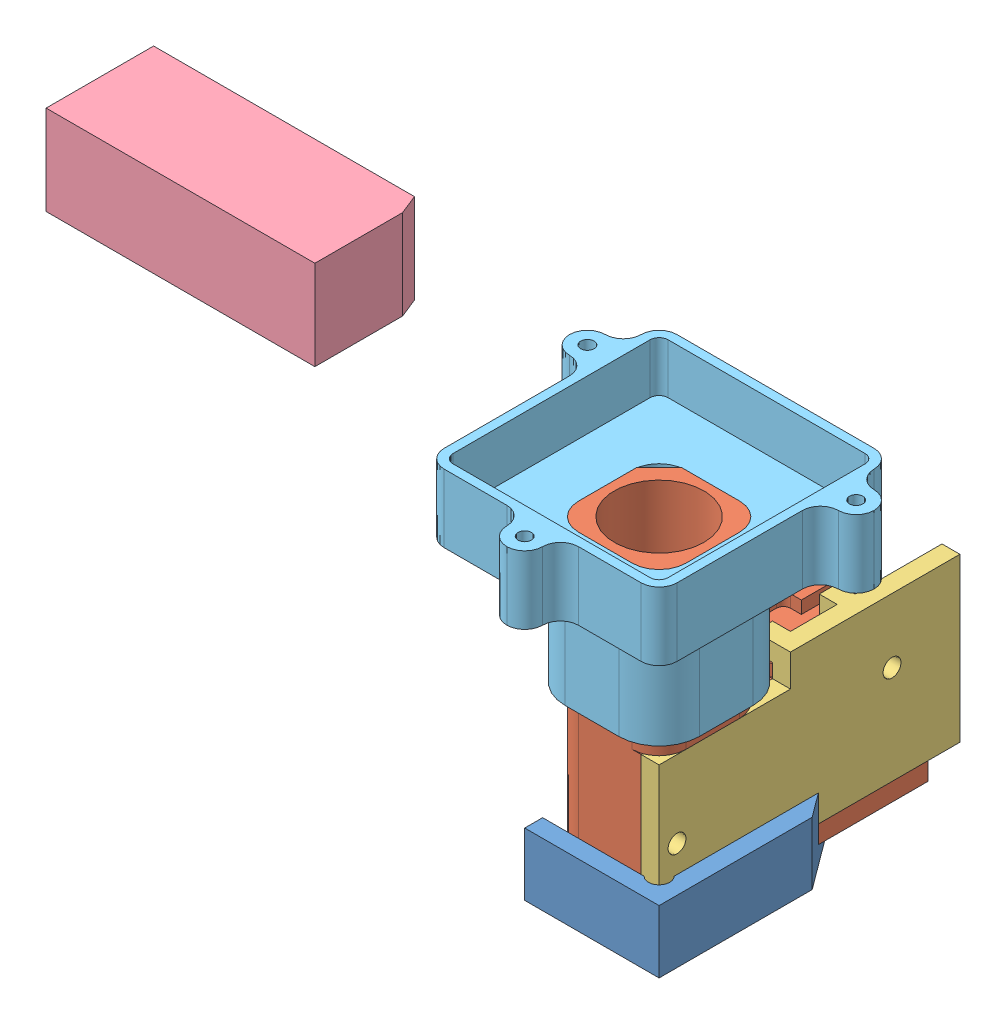
SolidWorks assembly Assembled_Modified_Miniscope, configuration Default. Lengths in mm.
Overall size (42.4 21.25 22.66).
5 component instances, 5 part files, 10 mates.
Components (placement in the parent):
- MS_Baseplatev3-1: MS_Baseplatev3 [Default] at origin size (8.46 3.5 18.16)
- MS_MainBodyv3.2-1: MS_MainBodyv3.2 [Default] at (-0.25 1 0.25) x (0 0 -1) z (1 0 0) size (15 17.3 6)
- MS_FilterCoverv3-1: MS_FilterCoverv3 [Default] at (2.75 5.25 0.25) x (0 0 1) z (-1 0 0) size (16.79 9.09 2)
- MS_CAPv3-1: MS_CAPv3 [Default] at (-26.6536 16.2484 2.0573) size (15 5 6)
- MS_FocusSliderv3.2-1: MS_FocusSliderv3.2 [Default] at (-0.25 10.3 4.75) x (0 0 -1) z (1 0 0) size (15 10.8 17)
Mates (geometry in assembly coordinates):
- Concentric1: concentric: cylinder of MS_MainBodyv3.2-1 through (-1.75 9.3 6.25) axis (0 -1 0) radius 1.5; cylinder of MS_FocusSliderv3.2-1 through (-1.75 21.1 6.25) axis (0 1 0) radius 1.5
- Concentric2: concentric: cylinder of MS_MainBodyv3.2-1 through (2.75 5 6.75) axis (-1 0 0) radius 0.375; cylinder of MS_FilterCoverv3-1 through (2.75 5 6.75) axis (1 0 0) radius 0.5
- Concentric3: concentric: cylinder of MS_Baseplatev3-1 through (-0.25 0 4.75) axis (0 1 0) radius 1.5; cylinder of MS_MainBodyv3.2-1 through (-0.25 18.3 4.75) axis (0 -1 0) radius 1.25
- Coincident3: coincident: plane of MS_Baseplatev3-1 through (0 1 0) normal (0 1 0); plane of MS_MainBodyv3.2-1 through (-0.25 1 0.25) normal (0 -1 0)
- Coincident4: coincident: plane of MS_Baseplatev3-1 through (2.75 -16.4469 -7.75) normal (-1 0 0); plane of MS_MainBodyv3.2-1 through (2.75 9.3 -7.25) normal (1 0 0)
- Tangent1: tangent: cylinder of MS_MainBodyv3.2-1 through (-1.75 9.3 6.25) axis (0 -1 0) radius 1.5; cylinder of MS_FocusSliderv3.2-1 through (-1.75 21.1 6.25) axis (0 1 0) radius 1.5
- Tangent2: tangent: cylinder of MS_MainBodyv3.2-1 through (1.25 18.3 3.25) axis (0 -1 0) radius 1.5; cylinder of MS_FocusSliderv3.2-1 through (1.25 21.1 3.25) axis (0 1 0) radius 1.5
- Concentric6: concentric: cylinder of MS_MainBodyv3.2-1 through (2.75 7.5 -5.25) axis (-1 0 0) radius 0.375; cylinder of MS_FilterCoverv3-1 through (2.75 7.5 -5.25) axis (1 0 0) radius 0.5
- Coincident6: coincident: plane of MS_MainBodyv3.2-1 through (-0.25 18.3 0.25) normal (0 1 0); plane of MS_FocusSliderv3.2-1 through (-0.25 18.3 4.75) normal (0 1 0)
- Coincident8: coincident: plane of MS_MainBodyv3.2-1 through (1.75 1 0.25) normal (1 0 0); plane of MS_FilterCoverv3-1 through (1.75 2 0) normal (-1 0 0)
